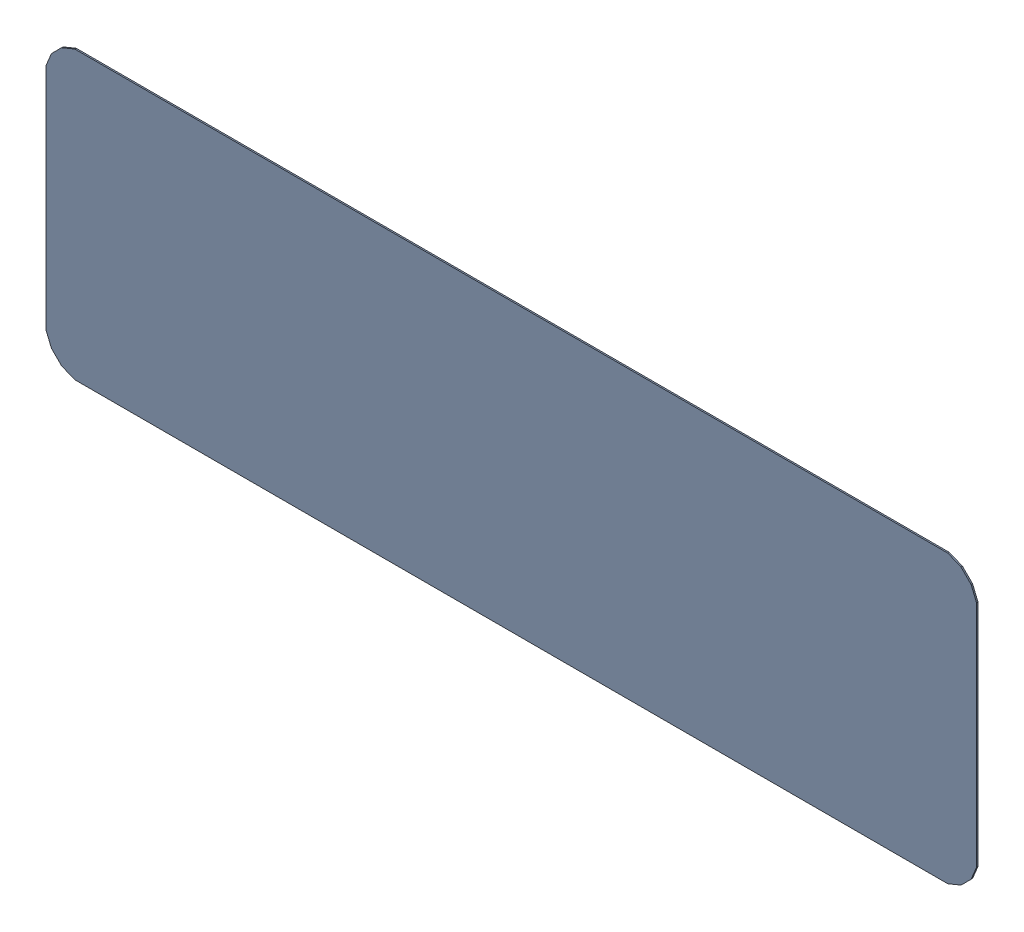
SolidWorks assembly LBL1, configuration Default. Lengths in mm.
Overall size (16.51 5.08 0.03).
2 component instances, 1 part files, 0 mates.
Components (placement in the parent):
- 6638389968-1: 6638389968 [Default] at (28.194 25.4 -1.6408) size (16.51 5.08 0.03)
  - Extruded_22-1: Extruded_22 [Default] at origin size (16.51 5.08 0.03)
